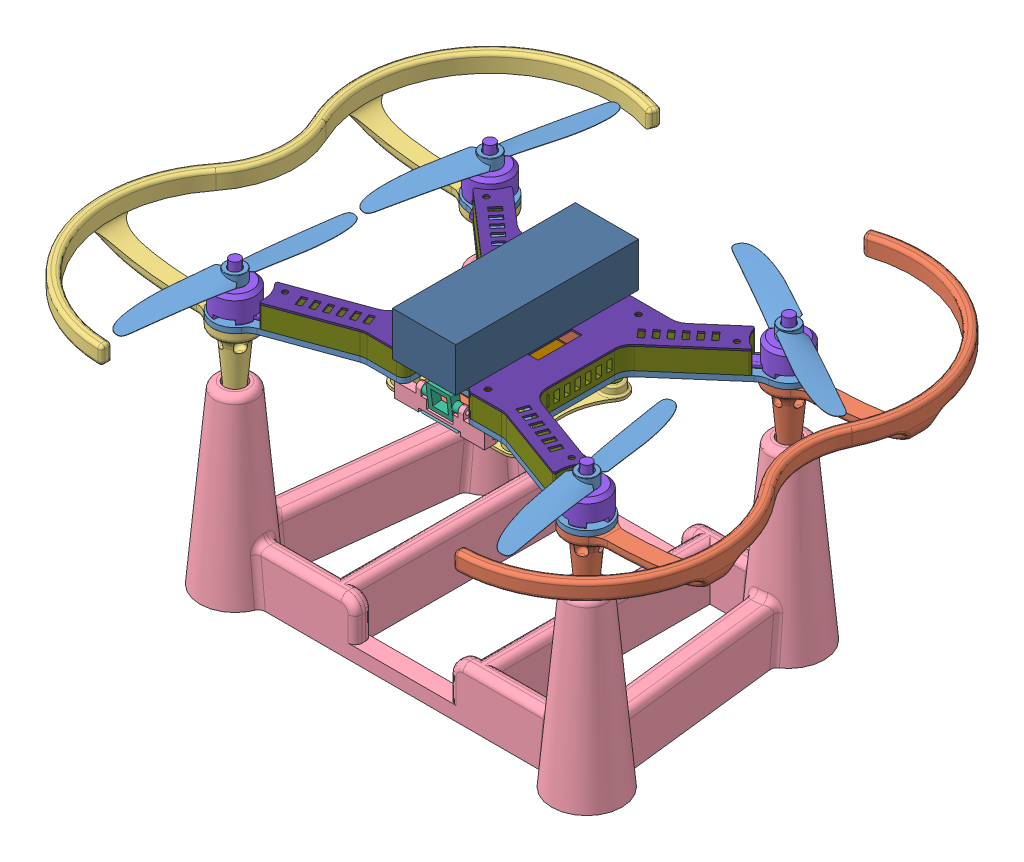
SolidWorks assembly assembly, configuration Default. Lengths in mm.
Overall size (352.07 173 281.97).
42 component instances, 24 part files, 95 mates.
Components (placement in the parent):
- base_plate-1: base_plate [Default] at origin size (225 3 155)
- subassem_snapdragon_flight-1: subassem_snapdragon_flight [Default] at (0 -13 -1.9278) size (78 19.86 75.36)
  - Snapdragon_Flight-1: Snapdragon_Flight [Default] at (0 6.5 7) x (0 0 1) z (-1 0 0) size (58 8.6 44.9)
  - mounting_plate-1: mounting_plate [Default] x (-1 0 0) z (0 0 -1) size (78 6.5 70)
  - camera_mount-1: camera_mount [Default] at (-1.502 6.35 37.6824) x (1 0 0.000747) z (-0.000747 0 1) size (52 19.7 28) (hidden)
  - front_camera_mount-1: front_camera_mount [Default] at (0 1.5 39.5) x (-1 0 0) z (0 0 -1) size (51 13.7 12)
  - bottom_camera_mount-1: bottom_camera_mount [Default] at (0 2 17.5) x (-1 0 0) z (0 0 -1) size (21.3 3.5 24.5)
  - front_camera_mount2-1: front_camera_mount2 [Default] at (0 12.6 39.5) x (1 0 0) z (0 -0.126408 0.991978) size (20.8 14 5)
  - dampener-1: dampener [Default] at (-31.5 9.75 30) x (0 -1 0) z (0 0 1) size (13 8.5 8.5)
  - dampener-2: dampener [Default] at (31.5 9.75 30) x (0 -1 0) z (0.505421 0 0.862873) size (13 8.5 8.5)
  - dampener-3: dampener [Default] at (-31.5 9.75 -25) x (0 -1 0) z (0 0 1) size (13 8.5 8.5)
  - dampener-4: dampener [Default] at (31.5 9.75 -25) x (0 -1 0) z (0 0 1) size (13 8.5 8.5)
- motor-1: motor [Default] at (-100 3 56.397) x (0.348308 0 0.93738) z (-0.93738 0 0.348308) size (23 26 31.5)
- motor-2: motor [Default] at (100 3 56.397) x (0.338895 0 -0.940824) z (0.940824 0 0.338895) size (23 26 31.5)
- motor-3: motor [Default] at (-85 3 -73.603) x (-0.858207 0 0.513304) z (-0.513304 0 -0.858207) size (23 26 31.5)
- motor-4: motor [Default] at (85 3 -73.603) x (-0.655102 0 -0.755541) z (0.755541 0 -0.655102) size (23 26 31.5)
- esc_board-1: esc_board [Default] at (0 8 5.5722) size (61.6 10 41)
- zippy_2200mah-1: zippy_2200mah [Default] at (0 16 -3.1077) x (0 0 -1) z (0 1 0) size (104 36 25)
- R110X-1: R110X [Default] at (18.0111 5 -24.6898) size (27 10 19)
- XT60 Stecker-1: XT60 Stecker [Default] at (-0.0414 7 -41) x (1 0 0) z (0 0 -1) size (15.68 8.08 21.4)
- plastic_insert_M3_94100A110_4.22hole-1: plastic_insert_M3_94100A110_4.22hole [Default] at (-23.25 -1.5 -11.9278) size (5.56 3.03 5.56)
- plastic_insert_M3_94100A110_4.22hole-2: plastic_insert_M3_94100A110_4.22hole [Default] at (23.25 -1.5 -11.9278) size (5.56 3.03 5.56)
- plastic_insert_M3_94100A110_4.22hole-3: plastic_insert_M3_94100A110_4.22hole [Default] at (23.25 -1.5 23.0722) size (5.56 3.03 5.56)
- plastic_insert_M3_94100A110_4.22hole-6: plastic_insert_M3_94100A110_4.22hole [Default] at (-23.25 -1.5 23.0722) size (5.56 3.03 5.56)
- terranger_one-1: terranger_one [Default] at (0 -4 -39.4278) x (-1 0 0) z (0 -1 0) size (46 33 17.61)
- dampener-1: dampener [Default] at (31.5 -3.25 28.0722) x (0 -1 0) z (0 0 1) size (13 8.5 8.5)
- plastic_insert_2-56_94648A310_3.73hole-1: plastic_insert_2-56_94648A310_3.73hole [Default] at (-20.25 4.778 -36.9278) x (-0.837169 0 -0.546944) z (-0.546944 0 0.837169) size (5.59 3.3 5.59)
- plastic_insert_2-56_94648A310_3.73hole-2: plastic_insert_2-56_94648A310_3.73hole [Default] at (20.25 4.778 -36.9278) x (-0.837169 0 -0.546944) z (-0.546944 0 0.837169) size (5.59 3.3 5.59)
- middle-1: middle [Default] at (0 3 0) size (177.67 12 128.43)
- top_plate2-1: top_plate2 [Default] at (0 15 0) size (178.23 1 128.93)
- wifi_antenna_FXP522.A.07.A.001-1: wifi_antenna_FXP522.A.07.A.001 [Default] at (0.168 -13.225 1.3368) size (80 0.15 20) (hidden)
- standoff_m3_12mm_95947A008-1: standoff_m3_12mm_95947A008 [Default] at (-30 3 -43) size (5.2 12 4.5)
- standoff_m3_12mm_95947A008-2: standoff_m3_12mm_95947A008 [Default] at (30 3 -43) size (5.2 12 4.5)
- standoff_m3_12mm_95947A008-3: standoff_m3_12mm_95947A008 [Default] at (-24 3 36.5722) size (5.2 12 4.5)
- standoff_m3_12mm_95947A008-4: standoff_m3_12mm_95947A008 [Default] at (24 3 36.5722) size (5.2 12 4.5)
- prop_5x3-1: prop_5x3 [Défaut] at (-85 17.5 -73.603) x (-0.216117 0 0.976367) z (-0.976367 0 -0.216117) size (127.6 6.5 14.71)
- prop_5x3-2: prop_5x3 [Défaut] at (85 17.5 -73.603) x (0.872028 0 0.489456) z (-0.489456 0 0.872028) size (127.6 6.5 14.71)
- prop_5x3-3: prop_5x3 [Défaut] at (-100 17.5 56.397) x (0.12988 0 -0.99153) z (0.99153 0 0.12988) size (127.6 6.5 14.71)
- prop_5x3-4: prop_5x3 [Défaut] at (100 17.5 56.397) x (-0.164662 0 -0.98635) z (0.98635 0 -0.164662) size (127.6 6.5 14.71)
- guard-1: guard [Default] at (0 12.5 -5.5707) size (116.46 57.5 281.97)
- guard_mirror-2: guard_mirror [Default] at (0 12.5 -5.5707) x (-1 0 0) z (0 0 -1) size (116.46 57.5 281.97)
- launch_stand-1: launch_stand [Default] at (0 -132 -3.603) x (-1 0 0) z (0 0 -1) size (240 100 170)
Mates (geometry in assembly coordinates):
- Coincident1: coincident aligned: plane of base_plate-1 through (0 0 0) normal (0 0 1); plane of assembly through (0 0 0) normal (0 0 1)
- Coincident2: coincident aligned: plane of base_plate-1 through (0 0 0) normal (0 1 0); plane of assembly through (0 0 0) normal (0 1 0)
- Coincident3: coincident aligned: plane of base_plate-1 through (0 0 0) normal (1 0 0); plane of assembly through (0 0 0) normal (1 0 0)
- Coincident4: coincident anti-aligned: plane of base_plate-1 through (0 0 0) normal (1 0 0); plane of ? through (0 -7.7242 0.1174) normal (-1 0 0)
- Coincident5: coincident anti-aligned: plane of ? through (0 -1.75 12) normal (-1 0 0); plane of assembly through (0 0 0) normal (1 0 0)
- Coincident8: coincident anti-aligned: plane of base_plate-1 through (75 0 -75) normal (0 -1 0); plane of ? through (16.5 0 -22) normal (0 1 0)
- Concentric1: concentric aligned: cylinder of base_plate-1 through (-31.5 0 35) axis (0 1 0) radius 3.1; cylinder of ? through (-31.5 -9.75 35) axis (0 1 0) radius 1.75
- Coincident10: coincident anti-aligned: plane of base_plate-1 through (75 3 -75) normal (0 1 0); plane of ? through (-26 3 45.6478) normal (0 -1 0)
- Concentric4: concentric aligned: cylinder of base_plate-1 through (-23.5 0 38.1478) axis (0 1 0) radius 1.1; cylinder of ? through (-23.5 1 38.1478) axis (0 1 0) radius 1
- Concentric6: concentric aligned: cylinder of base_plate-1 through (-100 3 56.397) axis (0 -1 0) radius 12.5; cylinder of motor-1 through (-100 17.5 56.397) axis (0 -1 0) radius 11.5
- Coincident11: coincident anti-aligned: plane of base_plate-1 through (85 3 -73.603) normal (0 1 0); plane of motor-1 through (-100 3 56.397) normal (0 -1 0)
- Concentric7: concentric aligned: cylinder of base_plate-1 through (100 3 56.397) axis (0 -1 0) radius 12.5; cylinder of motor-2 through (100 17.5 56.397) axis (0 -1 0) radius 11.5
- Concentric8: concentric aligned: cylinder of base_plate-1 through (85 3 -73.603) axis (0 -1 0) radius 12.5; cylinder of motor-4 through (85 17.5 -73.603) axis (0 -1 0) radius 11.5
- Concentric9: concentric aligned: cylinder of base_plate-1 through (-85 3 -73.603) axis (0 -1 0) radius 12.5; cylinder of motor-3 through (-85 17.5 -73.603) axis (0 -1 0) radius 11.5
- Coincident12: coincident anti-aligned: plane of base_plate-1 through (85 3 -73.603) normal (0 1 0); plane of motor-3 through (-85 3 -73.603) normal (0 -1 0)
- Coincident13: coincident anti-aligned: plane of base_plate-1 through (85 3 -73.603) normal (0 1 0); plane of motor-4 through (85 3 -73.603) normal (0 -1 0)
- Coincident14: coincident anti-aligned: plane of base_plate-1 through (85 3 -73.603) normal (0 1 0); plane of motor-2 through (100 3 56.397) normal (0 -1 0)
- Coincident17: coincident anti-aligned: plane of zippy_2200mah-1 through (0 16 -3.1077) normal (-1 0 0); plane of assembly through (0 0 0) normal (1 0 0)
- Concentric11: concentric aligned: cylinder of base_plate-1 through (23.5 0 38.1478) axis (0 1 0) radius 1.1; cylinder of ? through (23.5 1 38.1478) axis (0 1 0) radius 1
- Coincident20: coincident anti-aligned: plane of ? through (0 25.0406 -70.3519) normal (-1 0 0); plane of assembly through (0 0 0) normal (1 0 0)
- Concentric16: concentric anti-aligned: cylinder of base_plate-1 through (-23.25 0 -11.9278) axis (0 1 0) radius 2.11; cylinder of plastic_insert_M3_94100A110_4.22hole-1 through (-23.25 1.53 -11.9278) axis (0 -1 0) radius 2.34
- Coincident21: coincident anti-aligned: plane of base_plate-1 through (85 0 -73.603) normal (0 -1 0); plane of plastic_insert_M3_94100A110_4.22hole-1 through (-23.25 0 -11.9278) normal (0 1 0)
- Concentric17: concentric aligned: cylinder of base_plate-1 through (-23.25 0 -23.8522) axis (0 1 0) radius 2.11; cylinder of ? through (-23.25 1.47 -23.8522) axis (0 1 0) radius 2.34
- Coincident22: coincident anti-aligned: plane of base_plate-1 through (75 3 -75) normal (0 1 0); plane of ? through (-23.25 3 -23.8522) normal (0 -1 0)
- Concentric18: concentric anti-aligned: cylinder of base_plate-1 through (-23.25 0 11.1478) axis (0 1 0) radius 2.11; cylinder of ? through (-23.25 4.5 11.1478) axis (0 -1 0) radius 1.6
- Coincident23: coincident anti-aligned: plane of base_plate-1 through (75 3 -75) normal (0 1 0); plane of ? through (-23.25 3 11.1478) normal (0 -1 0)
- Concentric19: concentric anti-aligned: cylinder of base_plate-1 through (-23.25 0 23.0722) axis (0 1 0) radius 2.11; cylinder of plastic_insert_M3_94100A110_4.22hole-6 through (-23.25 1.53 23.0722) axis (0 -1 0) radius 2.34
- Coincident24: coincident anti-aligned: plane of base_plate-1 through (85 0 -73.603) normal (0 -1 0); plane of plastic_insert_M3_94100A110_4.22hole-6 through (-23.25 0 23.0722) normal (0 1 0)
- Concentric20: concentric anti-aligned: cylinder of base_plate-1 through (23.25 0 23.0722) axis (0 1 0) radius 2.11; cylinder of plastic_insert_M3_94100A110_4.22hole-3 through (23.25 1.53 23.0722) axis (0 -1 0) radius 2.34
- Coincident25: coincident anti-aligned: plane of base_plate-1 through (85 0 -73.603) normal (0 -1 0); plane of plastic_insert_M3_94100A110_4.22hole-3 through (23.25 0 23.0722) normal (0 1 0)
- Concentric21: concentric anti-aligned: cylinder of base_plate-1 through (23.25 0 -11.9278) axis (0 1 0) radius 2.11; cylinder of plastic_insert_M3_94100A110_4.22hole-2 through (23.25 1.53 -11.9278) axis (0 -1 0) radius 2.34
- Coincident26: coincident anti-aligned: plane of base_plate-1 through (85 0 -73.603) normal (0 -1 0); plane of plastic_insert_M3_94100A110_4.22hole-2 through (23.25 0 -11.9278) normal (0 1 0)
- Concentric22: concentric aligned: cylinder of base_plate-1 through (23.25 0 -23.8522) axis (0 1 0) radius 2.11; cylinder of ? through (23.25 1.47 -23.8522) axis (0 1 0) radius 2.34
- Coincident27: coincident anti-aligned: plane of base_plate-1 through (75 3 -75) normal (0 1 0); plane of ? through (23.25 3 -23.8522) normal (0 -1 0)
- Concentric23: concentric aligned: cylinder of base_plate-1 through (23.25 0 11.1478) axis (0 1 0) radius 2.11; cylinder of ? through (23.25 1.47 11.1478) axis (0 1 0) radius 2.34
- Coincident28: coincident anti-aligned: plane of base_plate-1 through (75 3 -75) normal (0 1 0); plane of ? through (23.25 3 11.1478) normal (0 -1 0)
- Distance1: distance = 5 mm anti-aligned: plane of base_plate-1 through (85 3 -73.603) normal (0 1 0); plane of esc_board-1 through (0 8 5.5722) normal (0 -1 0)
- Concentric34: concentric aligned: cylinder of base_plate-1 through (-23.25 0 23.0722) axis (0 1 0) radius 2.11; cylinder of esc_board-1 through (-23.25 4 23.0722) axis (0 1 0) radius 1.6
- Concentric35: concentric aligned: cylinder of base_plate-1 through (23.25 0 23.0722) axis (0 1 0) radius 2.11; cylinder of esc_board-1 through (23.25 4 23.0722) axis (0 1 0) radius 1.6
- Concentric36: concentric anti-aligned: cylinder of subassem_snapdragon_flight-1/mounting_plate-1 through (31.5 -13 28.0722) axis (0 1 0) radius 3.1; cylinder of dampener-1 through (31.5 -9.75 28.0722) axis (0 -1 0) radius 3
- Coincident36: coincident anti-aligned: plane of subassem_snapdragon_flight-1/mounting_plate-1 through (31.5 -6.5 28.0722) normal (0 1 0); plane of dampener-1 through (35.75 -6.5 28.0722) normal (0 -1 0)
- Concentric37: concentric anti-aligned: cylinder of base_plate-1 through (-31.5 0 -26.9278) axis (0 1 0) radius 3.1; cylinder of subassem_snapdragon_flight-1/dampener-3 through (-31.5 -9.75 -26.9278) axis (0 -1 0) radius 3
- Coincident37: coincident anti-aligned: plane of base_plate-1 through (85 0 -73.603) normal (0 -1 0); plane of subassem_snapdragon_flight-1/dampener-3 through (-28.5 0 -26.9278) normal (0 1 0)
- Concentric38: concentric anti-aligned: cylinder of base_plate-1 through (31.5 0 -26.9278) axis (0 1 0) radius 3.1; cylinder of subassem_snapdragon_flight-1/dampener-4 through (31.5 -9.75 -26.9278) axis (0 -1 0) radius 3
- Coincident38: coincident anti-aligned: plane of base_plate-1 through (85 0 -73.603) normal (0 -1 0); plane of terranger_one-1 through (0 0 -39.4278) normal (0 1 0)
- Concentric39: concentric aligned: cylinder of base_plate-1 through (20.25 0 -36.9278) axis (0 1 0) radius 1.875; cylinder of terranger_one-1 through (20.25 -17.6088 -36.9278) axis (0 1 0) radius 1.25
- Concentric40: concentric aligned: cylinder of base_plate-1 through (-20.25 0 -36.9278) axis (0 1 0) radius 1.875; cylinder of terranger_one-1 through (-20.25 -17.6088 -36.9278) axis (0 1 0) radius 1.25
- Coincident39: coincident anti-aligned: plane of base_plate-1 through (85 3 -73.603) normal (0 1 0); plane of plastic_insert_2-56_94648A310_3.73hole-1 through (-20.25 3 -36.9278) normal (0 -1 0)
- Concentric41: concentric anti-aligned: cylinder of base_plate-1 through (-20.25 0 -36.9278) axis (0 1 0) radius 1.875; cylinder of plastic_insert_2-56_94648A310_3.73hole-1 through (-20.25 4.778 -36.9278) axis (0 -1 0) radius 1.2192
- Coincident40: coincident anti-aligned: plane of base_plate-1 through (85 3 -73.603) normal (0 1 0); plane of plastic_insert_2-56_94648A310_3.73hole-2 through (20.25 3 -36.9278) normal (0 -1 0)
- Concentric42: concentric anti-aligned: cylinder of base_plate-1 through (20.25 0 -36.9278) axis (0 1 0) radius 1.875; cylinder of plastic_insert_2-56_94648A310_3.73hole-2 through (20.25 4.778 -36.9278) axis (0 -1 0) radius 1.2192
- Coincident41: coincident anti-aligned: plane of base_plate-1 through (85 3 -73.603) normal (0 1 0); plane of XT60 Stecker-1 through (7.7586 3 -41) normal (0 -1 0)
- Distance2: distance = 2 mm anti-aligned: plane of R110X-1 through (18.0111 5 -24.6898) normal (0 -1 0); plane of base_plate-1 through (85 3 -73.603) normal (0 1 0)
- Coincident44: coincident aligned: plane of base_plate-1 through (0 0 0) normal (0 0 1); plane of middle-1 through (0 3 0) normal (0 0 1)
- Coincident46: coincident aligned: plane of base_plate-1 through (0 0 0) normal (1 0 0); plane of middle-1 through (0 3 0) normal (1 0 0)
- Coincident47: coincident anti-aligned: plane of base_plate-1 through (85 3 -73.603) normal (0 1 0); plane of middle-1 through (14 3 -53) normal (0 -1 0)
- Coincident48: coincident aligned: plane of middle-1 through (0 3 0) normal (0 0 1); plane of top_plate2-1 through (0 15 0) normal (0 0 1)
- Coincident49: coincident aligned: plane of middle-1 through (0 3 0) normal (1 0 0); plane of top_plate2-1 through (0 15 0) normal (1 0 0)
- Coincident50: coincident anti-aligned: plane of middle-1 through (14 15 -53) normal (0 1 0); plane of top_plate2-1 through (14 15 -53) normal (0 -1 0)
- Coincident51: coincident anti-aligned: plane of zippy_2200mah-1 through (0 16 -3.1077) normal (0 -1 0); plane of top_plate2-1 through (14 16 -53) normal (0 1 0)
- Parallel1: parallel anti-aligned: plane of R110X-1 through (4.5111 9 -15.1898) normal (-1 0 0); plane of assembly through (0 0 0) normal (1 0 0)
- Coincident53: coincident anti-aligned: plane of XT60 Stecker-1 through (0.6035 7 -41) normal (0 0 1); plane of middle-1 through (-7 32.4642 -41) normal (0 0 -1)
- Concentric43: concentric aligned: cylinder of middle-1 through (-24 -13.9706 36.5722) axis (0 1 0) radius 3; cylinder of standoff_m3_12mm_95947A008-3 through (-24 3 36.5722) axis (0 1 0) radius 1.5
- Coincident54: coincident anti-aligned: plane of base_plate-1 through (85 3 -73.603) normal (0 1 0); plane of standoff_m3_12mm_95947A008-3 through (-24 3 36.5722) normal (0 -1 0)
- Coincident55: coincident anti-aligned: plane of base_plate-1 through (85 3 -73.603) normal (0 1 0); plane of standoff_m3_12mm_95947A008-4 through (24 3 36.5722) normal (0 -1 0)
- Concentric44: concentric aligned: cylinder of middle-1 through (24 -13.9706 36.5722) axis (0 1 0) radius 3; cylinder of standoff_m3_12mm_95947A008-4 through (24 3 36.5722) axis (0 1 0) radius 1.5
- Concentric45: concentric aligned: cylinder of middle-1 through (30 -13.9706 -43) axis (0 1 0) radius 3; cylinder of standoff_m3_12mm_95947A008-2 through (30 3 -43) axis (0 1 0) radius 1.5
- Concentric46: concentric aligned: cylinder of middle-1 through (-30 -13.9706 -43) axis (0 1 0) radius 3; cylinder of standoff_m3_12mm_95947A008-1 through (-30 3 -43) axis (0 1 0) radius 1.5
- Coincident56: coincident anti-aligned: plane of base_plate-1 through (85 3 -73.603) normal (0 1 0); plane of standoff_m3_12mm_95947A008-1 through (-30 3 -43) normal (0 -1 0)
- Coincident57: coincident anti-aligned: plane of base_plate-1 through (85 3 -73.603) normal (0 1 0); plane of standoff_m3_12mm_95947A008-2 through (30 3 -43) normal (0 -1 0)
- Concentric47: concentric aligned: cylinder of motor-1 through (-100 28.5 56.397) axis (0 -1 0) radius 3; cylinder of prop_5x3-3 through (-100 24 56.397) axis (0 -1 0) radius 2.5
- Coincident58: coincident anti-aligned: plane of motor-1 through (-100 17.5 56.397) normal (0 1 0); plane of prop_5x3-3 through (-100 17.5 56.397) normal (0 -1 0)
- Concentric48: concentric aligned: cylinder of motor-3 through (-85 28.5 -73.603) axis (0 -1 0) radius 3; cylinder of prop_5x3-1 through (-85 24 -73.603) axis (0 -1 0) radius 2.5
- Coincident59: coincident anti-aligned: plane of motor-3 through (-85 17.5 -73.603) normal (0 1 0); plane of prop_5x3-1 through (-85 17.5 -73.603) normal (0 -1 0)
- Coincident60: coincident anti-aligned: plane of motor-4 through (85 17.5 -73.603) normal (0 1 0); plane of prop_5x3-2 through (85 17.5 -73.603) normal (0 -1 0)
- Concentric49: concentric aligned: cylinder of motor-4 through (85 28.5 -73.603) axis (0 -1 0) radius 3; cylinder of prop_5x3-2 through (85 24 -73.603) axis (0 -1 0) radius 2.5
- Concentric50: concentric aligned: cylinder of motor-2 through (100 28.5 56.397) axis (0 -1 0) radius 3; cylinder of prop_5x3-4 through (100 24 56.397) axis (0 -1 0) radius 2.5
- Coincident61: coincident anti-aligned: plane of motor-2 through (100 17.5 56.397) normal (0 1 0); plane of prop_5x3-4 through (100 17.5 56.397) normal (0 -1 0)
- Coincident62: coincident: plane of middle-1 through (-14 15 -50) normal (0 0 -1); plane of ? through (-45.4548 4 -50) normal (0 0 -1)
- Distance3: distance = 1 mm anti-aligned: plane of base_plate-1 through (85 3 -75) normal (0 1 0); plane of ? through (-22.8209 2 -30) normal (0 -1 0)
- Concentric51: concentric anti-aligned: cylinder of base_plate-1 through (-70 0 -56.6458) axis (0 1 0) radius 1.865; cylinder of ? through (-70 1.524 -56.6458) axis (0 -1 0) radius 2.159
- Coincident63: coincident anti-aligned: plane of base_plate-1 through (85 0 -73.603) normal (0 -1 0); plane of ? through (-70 0 -56.6458) normal (0 1 0)
- Concentric52: concentric anti-aligned: cylinder of base_plate-1 through (80 0 45.9251) axis (0 1 0) radius 1.865; cylinder of ? through (80 1.524 45.9251) axis (0 -1 0) radius 2.159
- Coincident64: coincident anti-aligned: plane of base_plate-1 through (85 0 -73.603) normal (0 -1 0); plane of ? through (80 0 45.9251) normal (0 1 0)
- Concentric53: concentric anti-aligned: cylinder of base_plate-1 through (70 0 -56.6458) axis (0 1 0) radius 1.865; cylinder of ? through (70 1.524 -56.6458) axis (0 -1 0) radius 2.159
- Coincident65: coincident anti-aligned: plane of base_plate-1 through (85 0 -73.603) normal (0 -1 0); plane of ? through (80 0 45.9251) normal (0 1 0)
- Coincident66: coincident anti-aligned: plane of base_plate-1 through (85 0 -73.603) normal (0 -1 0); plane of ? through (70 0 -56.6458) normal (0 1 0)
- Concentric54: concentric anti-aligned: cylinder of base_plate-1 through (-80 0 45.9251) axis (0 1 0) radius 1.865; cylinder of ? through (-80 1.524 45.9251) axis (0 -1 0) radius 2.159
- Coincident67: coincident anti-aligned: plane of base_plate-1 through (85 0 -73.603) normal (0 -1 0); plane of ? through (-80 0 45.9251) normal (0 1 0)
- Concentric57: concentric aligned: cylinder of base_plate-1 through (85 3 -73.603) axis (0 -1 0) radius 12.5; cylinder of guard-1 through (85 0 -73.603) axis (0 -1 0) radius 12.5
- Concentric58: concentric aligned: cylinder of base_plate-1 through (100 3 56.397) axis (0 -1 0) radius 12.5; cylinder of guard-1 through (100 0 56.397) axis (0 -1 0) radius 12.5
- Coincident68: coincident anti-aligned: plane of base_plate-1 through (85 0 -73.603) normal (0 -1 0); plane of guard-1 through (99 0 -68.603) normal (0 1 0)
- Concentric59: concentric aligned: circle of guard_mirror-2; cylinder of launch_stand-1 through (-100 -35 56.397) axis (0 1 0) radius 6
- Concentric60: concentric anti-aligned: circle of guard-1; cylinder of launch_stand-1 through (100 -35 56.397) axis (0 1 0) radius 6
- Coincident69: coincident anti-aligned: plane of guard-1 through (100 -35 56.397) normal (0 -1 0); plane of launch_stand-1 through (100 -35 56.397) normal (0 1 0)
